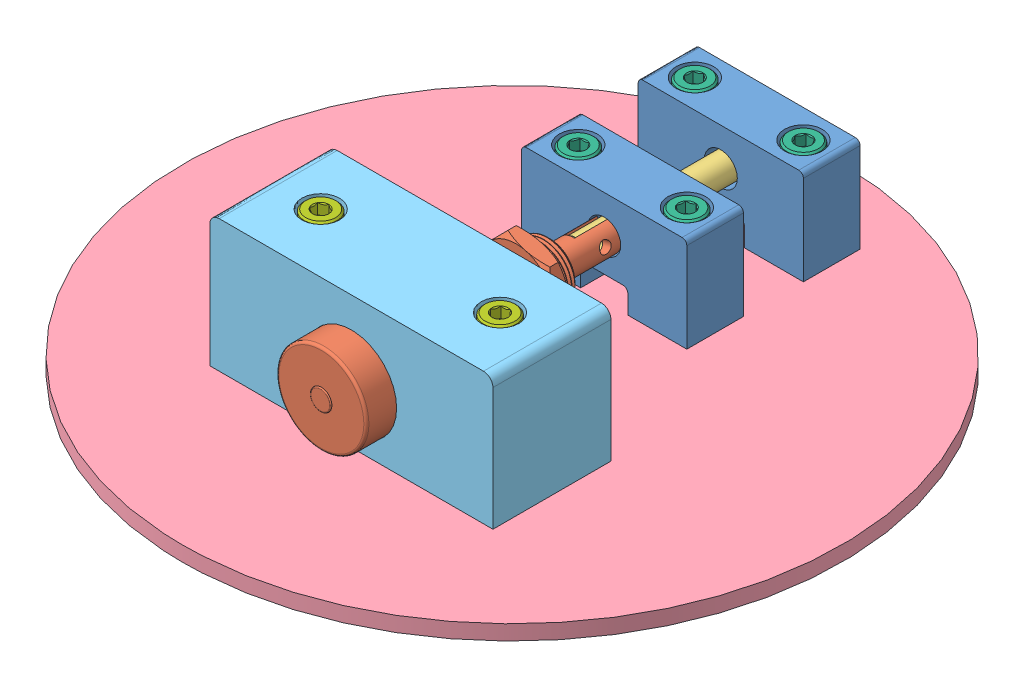
SolidWorks assembly Thesis4_assy, configuration Default. Lengths in mm.
Overall size (139.7 37.79 139.7).
12 component instances, 7 part files, 27 mates.
Components (placement in the parent):
- Thesis4_pin_block-1: Thesis4_pin_block [Default] at (0 3.175 -31.496) size (35 20 12)
- Thesis4_pin_block-2: Thesis4_pin_block [Default] at (0 3.175 -56.196) size (35 20 12)
- 69905K110_SEALED LINEAR SOLENOID-1: 69905K110_SEALED LINEAR SOLENOID [69905K11] at (0 15.175 1.567) x (-0.9643 -0.264812 0) z (0 0 -1) size (19.05 19.05 60.65)
- 98381A035_pin_modified-1: 98381A035_pin_modified [98381A035] at (0 15.175 -31.9356) x (0 0 -1) z (0.9643 0.264812 0) size (38.1 5.56 5.56)
- Thesis4_base_plate-1: Thesis4_base_plate [Default] at origin size (139.7 3.17 139.7)
- Thesis4_solenoid_housing-1: Thesis4_solenoid_housing [Default] at (0 3.175 21.579) size (60 28 25)
- 91292A122_TYPE 18-8 SS SOCKET HEAD CAP SCREW-1: 91292A122_TYPE 18-8 SS SOCKET HEAD CAP SCREW [91292A122] at (11.5 -5.825 -25.496) x (0.36243 0 0.932011) z (0 -1 0) size (7 7 29.79)
- 91292A130_TYPE 18-8 SS SOCKET HEAD CAP SCREW-1: 91292A130_TYPE 18-8 SS SOCKET HEAD CAP SCREW [91292A130] at (-19 -2.825 21.579) x (1 0 0) z (0 -1 0) size (7 7 34.79)
- 91292A122_TYPE 18-8 SS SOCKET HEAD CAP SCREW-2: 91292A122_TYPE 18-8 SS SOCKET HEAD CAP SCREW [91292A122] at (11.5 -5.825 -50.196) x (-0.881785 0 -0.471651) z (0 -1 0) size (7 7 29.79)
- 91292A122_TYPE 18-8 SS SOCKET HEAD CAP SCREW-3: 91292A122_TYPE 18-8 SS SOCKET HEAD CAP SCREW [91292A122] at (-11.5 -5.825 -25.496) x (0.815547 0 -0.57869) z (0 -1 0) size (7 7 29.79)
- 91292A122_TYPE 18-8 SS SOCKET HEAD CAP SCREW-4: 91292A122_TYPE 18-8 SS SOCKET HEAD CAP SCREW [91292A122] at (-11.5 -5.825 -50.196) x (0.569895 0 -0.821718) z (0 -1 0) size (7 7 29.79)
- 91292A130_TYPE 18-8 SS SOCKET HEAD CAP SCREW-2: 91292A130_TYPE 18-8 SS SOCKET HEAD CAP SCREW [91292A130] at (19 -2.825 21.579) x (0.194226 0 0.980957) z (0 -1 0) size (7 7 34.79)
Mates (geometry in assembly coordinates):
- Coincident1: coincident: plane of Thesis4_base_plate-1 through (0 0 0) normal (0 -1 0); plane of assembly through (0 0 0) normal (0 1 0)
- Coincident2: coincident: plane of Thesis4_base_plate-1 through (0 0 0) normal (0 0 1); plane of assembly through (0 0 0) normal (0 0 1)
- Coincident3: coincident: plane of Thesis4_base_plate-1 through (0 0 0) normal (1 0 0); plane of assembly through (0 0 0) normal (1 0 0)
- Coincident4: coincident: plane of Thesis4_pin_block-2 through (5 3.175 -44.196) normal (0 -1 0); plane of Thesis4_base_plate-1 through (0 3.175 0) normal (0 1 0)
- Coincident5: coincident: plane of Thesis4_pin_block-1 through (-5 3.175 -19.496) normal (0 -1 0); plane of Thesis4_base_plate-1 through (0 3.175 0) normal (0 1 0)
- Concentric1: concentric: cylinder of Thesis4_pin_block-1 through (0 15.175 -19.496) axis (0 0 -1) radius 3.5; cylinder of Thesis4_pin_block-2 through (0 15.175 -44.196) axis (0 0 -1) radius 3.5
- Concentric2: concentric: cylinder of Thesis4_pin_block-1 through (0 15.175 -19.496) axis (0 0 -1) radius 3.5; cylinder of 98381A035_pin_modified-1 through (0 15.175 -12.8856) axis (0 0 -1) radius 2.7781
- Distance3: distance = 0 mm: plane of assembly through (0 0 0) normal (1 0 0); cylinder of Thesis4_pin_block-2 through (0 15.175 -44.196) axis (0 0 -1) radius 3.5
- Distance4: distance = 44.196 mm: plane of assembly through (0 0 0) normal (0 0 1); plane of Thesis4_pin_block-2 through (0 3.175 -44.196) normal (0 0 1)
- Distance5: distance = 12.7 mm: plane of Thesis4_pin_block-1 through (0 3.175 -31.496) normal (0 0 -1); plane of Thesis4_pin_block-2 through (0 3.175 -44.196) normal (0 0 1)
- Concentric3: concentric: cylinder of 69905K110_SEALED LINEAR SOLENOID-1 through (0 15.175 1.567) axis (0 0 1) radius 3.175; cylinder of 98381A035_pin_modified-1 through (0 15.175 -12.8856) axis (0 0 -1) radius 2.7781
- Concentric4: concentric: cylinder of 69905K110_SEALED LINEAR SOLENOID-1 through (-9.1859 12.6524 -16.6956) axis (0.9643 0.264812 0) radius 1.1938; cylinder of 98381A035_pin_modified-1 through (-2.6789 14.4393 -16.6956) axis (0.9643 0.264812 0) radius 1.1906
- Concentric5: concentric: cylinder of 69905K110_SEALED LINEAR SOLENOID-1 through (0 15.175 40.65) axis (0 0 1) radius 9.525; cylinder of Thesis4_solenoid_housing-1 through (0 15.175 9.079) axis (0 0 1) radius 9.5885
- Distance6: distance = 6.35 mm: plane of 69905K110_SEALED LINEAR SOLENOID-1 through (0.5899 13.0269 40.429) normal (0 0 1); plane of Thesis4_solenoid_housing-1 through (-30 31.175 34.079) normal (0 0 1)
- Concentric6: concentric: cylinder of Thesis4_solenoid_housing-1 through (19 31.175 21.579) axis (0 1 0) radius 4; cylinder of 91292A130_TYPE 18-8 SS SOCKET HEAD CAP SCREW-2 through (19 31.175 21.579) axis (0 -1 0) radius 3.5
- Concentric7: concentric: cylinder of Thesis4_solenoid_housing-1 through (-19 31.175 21.579) axis (0 1 0) radius 4; cylinder of 91292A130_TYPE 18-8 SS SOCKET HEAD CAP SCREW-1 through (-19 31.175 21.579) axis (0 -1 0) radius 3.5
- Coincident10: coincident: plane of Thesis4_solenoid_housing-1 through (-16.75 27.175 21.579) normal (0 1 0); plane of 91292A130_TYPE 18-8 SS SOCKET HEAD CAP SCREW-1 through (-19 27.175 21.579) normal (0 -1 0)
- Coincident11: coincident: plane of Thesis4_solenoid_housing-1 through (21.25 27.175 21.579) normal (0 1 0); plane of 91292A130_TYPE 18-8 SS SOCKET HEAD CAP SCREW-2 through (19 27.175 21.579) normal (0 -1 0)
- Concentric8: concentric: cylinder of Thesis4_pin_block-1 through (-11.5 23.175 -25.496) axis (0 1 0) radius 4; cylinder of 91292A122_TYPE 18-8 SS SOCKET HEAD CAP SCREW-3 through (-11.5 23.175 -25.496) axis (0 -1 0) radius 3.5
- Concentric9: concentric: cylinder of Thesis4_pin_block-1 through (11.5 23.175 -25.496) axis (0 1 0) radius 4; cylinder of 91292A122_TYPE 18-8 SS SOCKET HEAD CAP SCREW-1 through (11.5 23.175 -25.496) axis (0 -1 0) radius 3.5
- Concentric10: concentric: cylinder of Thesis4_pin_block-2 through (-11.5 23.175 -50.196) axis (0 1 0) radius 4; cylinder of 91292A122_TYPE 18-8 SS SOCKET HEAD CAP SCREW-4 through (-11.5 23.175 -50.196) axis (0 -1 0) radius 3.5
- Concentric11: concentric: cylinder of Thesis4_pin_block-2 through (11.5 23.175 -50.196) axis (0 1 0) radius 4; cylinder of 91292A122_TYPE 18-8 SS SOCKET HEAD CAP SCREW-2 through (11.5 23.175 -50.196) axis (0 -1 0) radius 3.5
- Coincident12: coincident: plane of Thesis4_pin_block-1 through (-9.25 19.175 -25.496) normal (0 1 0); plane of 91292A122_TYPE 18-8 SS SOCKET HEAD CAP SCREW-3 through (-11.5 19.175 -25.496) normal (0 -1 0)
- Coincident13: coincident: plane of Thesis4_pin_block-1 through (13.75 19.175 -25.496) normal (0 1 0); plane of 91292A122_TYPE 18-8 SS SOCKET HEAD CAP SCREW-1 through (11.5 19.175 -25.496) normal (0 -1 0)
- Coincident14: coincident: plane of Thesis4_pin_block-2 through (-9.25 19.175 -50.196) normal (0 1 0); plane of 91292A122_TYPE 18-8 SS SOCKET HEAD CAP SCREW-4 through (-11.5 19.175 -50.196) normal (0 -1 0)
- Coincident15: coincident: plane of Thesis4_pin_block-2 through (13.75 19.175 -50.196) normal (0 1 0); plane of 91292A122_TYPE 18-8 SS SOCKET HEAD CAP SCREW-2 through (11.5 19.175 -50.196) normal (0 -1 0)
- Distance7: distance = 28.575 mm: plane of Thesis4_solenoid_housing-1 through (-30 31.175 9.079) normal (0 0 -1); plane of Thesis4_pin_block-1 through (0 3.175 -19.496) normal (0 0 1)
